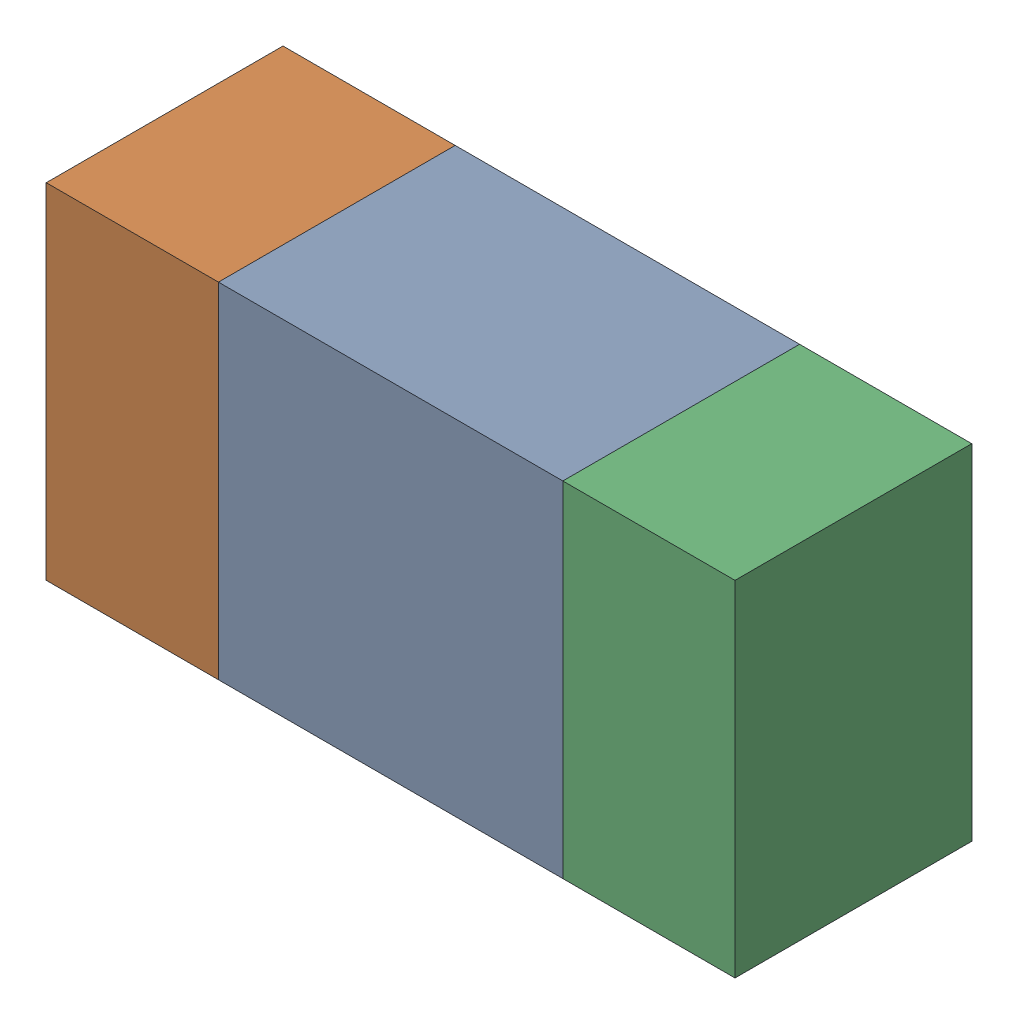
SolidWorks assembly R57, configuration ﾃﾞﾌｫﾙﾄ. Lengths in mm.
Overall size (1.6 0.8 0.55).
6 component instances, 2 part files, 0 mates.
Components (placement in the parent):
- 689261648-1: 689261648 [ﾃﾞﾌｫﾙﾄ] at (44.2 24.1999 0) size (0.8 0.8 0.55)
  - Extruded_33-1: Extruded_33 [ﾃﾞﾌｫﾙﾄ] at origin size (0.8 0.8 0.55)
- 689261512-1: 689261512 [ﾃﾞﾌｫﾙﾄ] at (43.5999 24.1999 0) size (0.4 0.8 0.55)
  - Extruded_32-1: Extruded_32 [ﾃﾞﾌｫﾙﾄ] at origin size (0.4 0.8 0.55)
- 689261512-2: 689261512 [ﾃﾞﾌｫﾙﾄ] at (44.7999 24.1999 0) size (0.4 0.8 0.55)
  - Extruded_32-1: Extruded_32 [ﾃﾞﾌｫﾙﾄ] at origin size (0.4 0.8 0.55)
